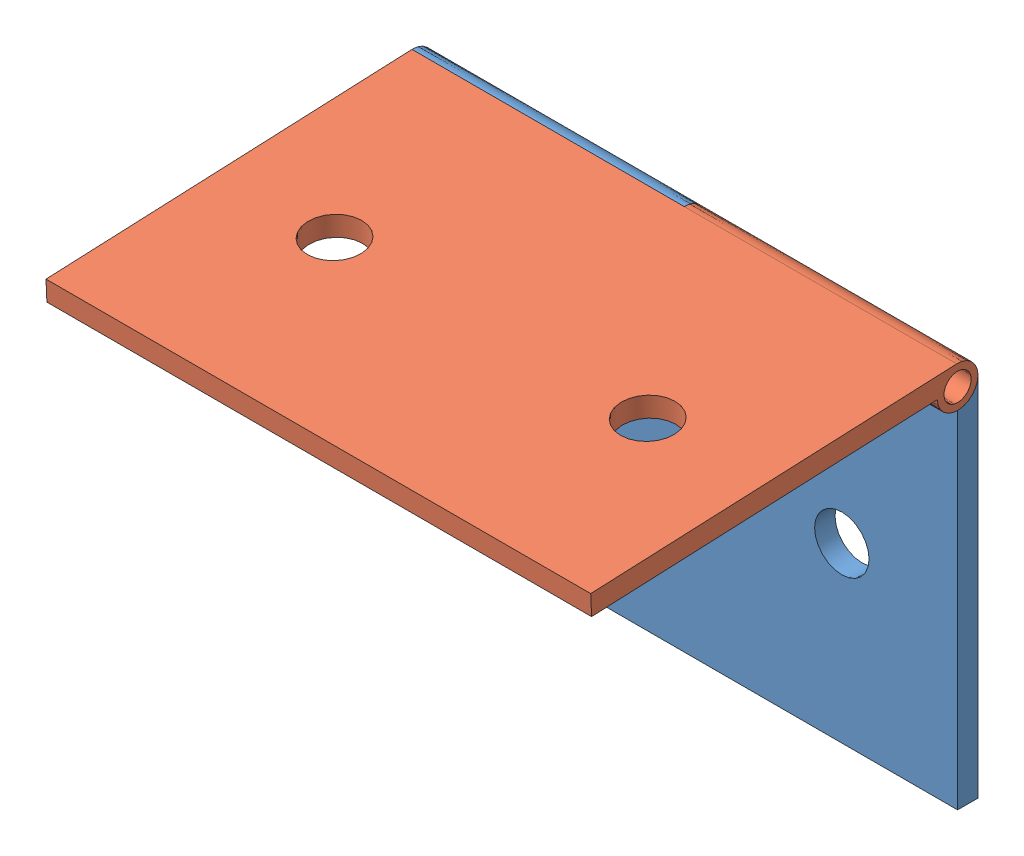
SolidWorks assembly bisagra conjunto, configuration Predeterminado. Lengths in mm.
Overall size (40 28.46 28.5).
2 component instances, 2 part files, 2 mates.
Components (placement in the parent):
- bisagra 01-1: bisagra 01 [Predeterminado] at (-38.1103 2.1851 8.1797) size (40 28.4 3)
- bisagra 02-1: bisagra 02 [Predeterminado] at (-38.1103 16.5157 23.1489) x (-1 0 0) z (0 -0.99905 -0.043568) size (40 28.4 3)
Mates (geometry in assembly coordinates):
- Concéntrica1: concentric: cylinder of assembly; cylinder of assembly; cylinder of bisagra 01-1 through (-58.1103 16.3851 8.9297) axis (1 0 0) radius 1; cylinder of bisagra 02-1 through (-18.1103 16.3851 8.9297) axis (-1 0 0) radius 1
- Coincidente1: coincident: plane of assembly; plane of assembly; plane of bisagra 01-1 through (-38.1103 16.3851 8.9297) normal (1 0 0); plane of bisagra 02-1 through (-38.1103 16.3851 8.9297) normal (-1 0 0)
